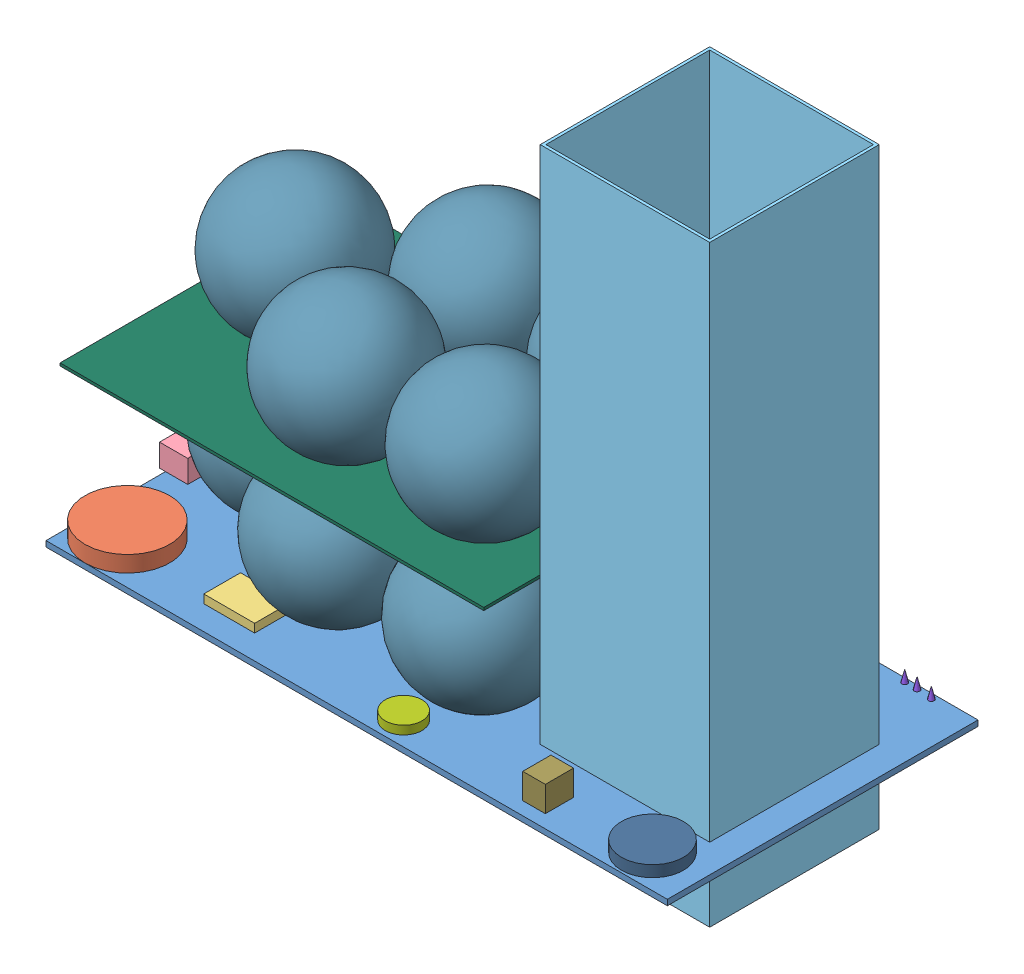
SolidWorks assembly layout_Assem1, configuration Default. Lengths in mm.
Overall size (2290.79 2100 2009.98).
28 component instances, 15 part files, 31 mates.
Components (placement in the parent):
- Rover_base-1: Rover_base [Default] at (-1064.6676 -0.8898 562.4151) size (2200 20 1100)
- Neutron_spectrometer-1: Neutron_spectrometer [Default] at (-926.7762 19.1102 412.2415) size (300 57 300)
- Neutron_spectrometer_electronics-1: Neutron_spectrometer_electronics [Default] at (-591.6675 19.1102 476.7062) size (180 30 130)
- gc-1: gc [Default] at (-1085.6976 19.1102 139.436) size (100 80 100)
- svr_box-1: svr_box [Default] at (435.3324 -241.6306 312.4151) size (600 2100 600)
- xrf-1: xrf [Default] at (-995.9409 19.1102 -179.1913) size (80 90 80)
- geotechnical_exp-1: geotechnical_exp [Default] at (118.8439 19.1102 479.7148) x (0.999975 0 -0.007135) z (0.007135 0 0.999975) size (130 30 130)
- penetrometer_3-1: penetrometer_3 [Default] at (989.1282 19.1102 -518.5473) x (-0.60186 0 0.798602) z (-0.798602 0 -0.60186) size (20 40 20)
- penetrometer_3-2: penetrometer_3 [Default] at (934.1975 19.1102 -522.9905) size (20 40 20)
- penetrometer_3-3: penetrometer_3 [Default] at (890.3988 19.1102 -523.0172) x (0.957231 0 -0.289323) z (0.289323 0 0.957231) size (20 40 20)
- power-1: power [Default] at (-567.0372 19.1102 -253.9622) size (180 90 96)
- geotechnical_exp_vane-1: geotechnical_exp_vane [Default] at (965.2252 19.1102 444.9326) size (220 40 220)
- Magnents-1: Magnents [Default] at (-1020.4169 -10.8898 98.2252) size (45 10 45)
- Becon-1: Becon [Default] at (656.9367 19.1102 515.9957) size (80 90 100)
- Belly Cam-1: Belly Cam [Default] at (-624.94 -100.8898 134.6139) size (150 100 150)
- power_tank-1: power_tank [Default] at (-887.862 555.3324 -63.369) x (-0.812429 0.027314 0.58242) z (0.582091 -0.01957 0.812888) size (1560.46 846.95 1367.46)
  - power_tank_10-1: power_tank_10 [Default] at (-67.1815 281.3265 414.5148) size (500 500 500)
  - power_tank_10-2: power_tank_10 [Default] at (-251.8267 476.4977 723.0274) x (0.786037 -0.315714 0.53148) z (0.083274 0.905991 0.415025) size (500 500 500)
  - power_tank_10-3: power_tank_10 [Default] at (-733.4982 325.3571 380.2859) x (0.665484 -0.133715 0.734337) z (-0.678573 0.301428 0.669836) size (500 500 500)
  - power_tank_10-4: power_tank_10 [Default] at (-1034.3616 424.6302 664.9742) x (0.724325 0.588989 -0.358392) z (-0.233278 0.698521 0.676499) size (500 500 500)
  - power_tank_10-5: power_tank_10 [Default] at (-695.3433 297.5492 1147.5051) x (0.994968 0.097333 0.023775) z (-0.042044 0.190197 0.980845) size (500 500 500)
- Tank_seperator_plate-1: Tank_seperator_plate [Default] at (435.3324 529.1102 512.4151) size (1500 10 1000)
- power_tank-3: power_tank [Default] at (-887.862 502.888 93.4377) x (-0.812429 -0.027314 -0.58242) z (0.582091 0.01957 -0.812888) size (1560.46 846.95 1367.46)
  - power_tank_10-1: power_tank_10 [Default] at (-67.1815 281.3265 414.5148) size (500 500 500)
  - power_tank_10-2: power_tank_10 [Default] at (-251.8267 476.4977 723.0274) x (0.786037 -0.315714 0.53148) z (0.083274 0.905991 0.415025) size (500 500 500)
  - power_tank_10-3: power_tank_10 [Default] at (-733.4982 325.3571 380.2859) x (0.665484 -0.133715 0.734337) z (-0.678573 0.301428 0.669836) size (500 500 500)
  - power_tank_10-4: power_tank_10 [Default] at (-1034.3616 424.6302 664.9742) x (0.724325 0.588989 -0.358392) z (-0.233278 0.698521 0.676499) size (500 500 500)
  - power_tank_10-5: power_tank_10 [Default] at (-695.3433 297.5492 1147.5051) x (0.994968 0.097333 0.023775) z (-0.042044 0.190197 0.980845) size (500 500 500)
Mates (geometry in assembly coordinates):
- Coincident2: coincident anti-aligned: plane of Rover_base-1 through (-1064.6676 19.1102 -537.5849) normal (0 1 0); plane of Neutron_spectrometer-1 through (-926.7762 19.1102 412.2415) normal (0 -1 0)
- Coincident6: coincident anti-aligned: plane of Rover_base-1 through (-1064.6676 19.1102 -537.5849) normal (0 1 0); plane of Neutron_spectrometer_electronics-1 through (-591.6675 19.1102 346.7062) normal (0 -1 0)
- Coincident7: coincident anti-aligned: plane of Rover_base-1 through (-1064.6676 19.1102 -537.5849) normal (0 1 0); plane of power-1 through (-567.0372 19.1102 -349.9622) normal (0 -1 0)
- Coincident8: coincident anti-aligned: plane of Rover_base-1 through (-1064.6676 19.1102 -537.5849) normal (0 1 0); plane of gc-1 through (-1085.6976 19.1102 39.436) normal (0 -1 0)
- Coincident9: coincident aligned: plane of Rover_base-1 through (-1064.6676 19.1102 -537.5849) normal (0 1 0); circle of geotechnical_exp-1 centre (118.8439 19.1102 479.7148) axis (0 1 0)
- Coincident10: coincident anti-aligned: plane of Rover_base-1 through (-1064.6676 19.1102 -537.5849) normal (0 1 0); plane of xrf-1 through (-995.9409 19.1102 -179.1913) normal (0 -1 0)
- Coincident11: coincident aligned: plane of Rover_base-1 through (-1064.6676 19.1102 -537.5849) normal (0 1 0); circle of penetrometer_3-3 centre (890.3988 19.1102 -523.0172) axis (0 1 0)
- Coincident12: coincident anti-aligned: plane of Rover_base-1 through (-1064.6676 19.1102 -537.5849) normal (0 1 0); plane of penetrometer_3-2 through (934.1975 19.1102 -522.9905) normal (0 -1 0)
- Coincident13: coincident aligned: plane of Rover_base-1 through (-1064.6676 19.1102 -537.5849) normal (0 1 0); circle of penetrometer_3-1 centre (989.1282 19.1102 -518.5473) axis (0 1 0)
- Coincident14: coincident anti-aligned: plane of Rover_base-1 through (-1064.6676 19.1102 -537.5849) normal (0 1 0); plane of geotechnical_exp_vane-1 through (965.2252 19.1102 444.9326) normal (0 -1 0)
- Coincident15: coincident anti-aligned: plane of Rover_base-1 through (-1064.6676 -0.8898 -537.5849) normal (0 -1 0); plane of Magnents-1 through (-1020.4169 -0.8898 98.2252) normal (0 1 0)
- Coincident16: coincident anti-aligned: plane of Rover_base-1 through (-1064.6676 19.1102 -537.5849) normal (0 1 0); plane of Becon-1 through (656.9367 19.1102 515.9957) normal (0 -1 0)
- Tangent1: tangent anti-aligned: plane of Rover_base-1 through (-1064.6676 19.1102 -537.5849) normal (0 1 0); sphere of power_tank-1/power_tank_10-1
- Coincident18: coincident: line of Rover_base-1; plane of svr_box-1 through (435.3324 1858.3694 312.4151) normal (-1 0 0)
- Coincident20: coincident: line of Rover_base-1; plane of svr_box-1 through (435.3324 1858.3694 -287.5849) normal (0 0 -1)
- Perpendicular2: perpendicular: line of Rover_base-1; line of svr_box-1
- Perpendicular3: perpendicular: line of Rover_base-1; line of svr_box-1
- Perpendicular4: perpendicular: line of Rover_base-1; line of svr_box-1
- Tangent12: tangent anti-aligned: plane of Rover_base-1 through (-1064.6676 19.1102 -537.5849) normal (0 1 0); sphere of power_tank-1/power_tank_10-4
- Tangent13: tangent anti-aligned: plane of Rover_base-1 through (-1064.6676 19.1102 -537.5849) normal (0 1 0); sphere of power_tank-1/power_tank_10-5
- Tangent15: tangent anti-aligned: plane of svr_box-1 through (435.3324 1858.3694 312.4151) normal (-1 0 0); sphere of power_tank-1/power_tank_10-4
- Tangent16: tangent anti-aligned: plane of svr_box-1 through (435.3324 1858.3694 312.4151) normal (-1 0 0); sphere of power_tank-1/power_tank_10-5
- Coincident25: coincident anti-aligned: plane of svr_box-1 through (435.3324 1858.3694 312.4151) normal (-1 0 0); plane of Tank_seperator_plate-1 through (435.3324 539.1102 512.4151) normal (1 0 0)
- Parallel1: parallel anti-aligned: plane of Rover_base-1 through (-1064.6676 19.1102 -537.5849) normal (0 1 0); plane of Tank_seperator_plate-1 through (435.3324 529.1102 512.4151) normal (0 -1 0)
- Distance3: distance = 200 mm: line of svr_box-1; point of Tank_seperator_plate-1
- Distance4: distance = 510 mm: plane of Rover_base-1 through (-1064.6676 19.1102 -537.5849) normal (0 1 0); line of Tank_seperator_plate-1
- Tangent29: tangent anti-aligned: plane of svr_box-1 through (435.3324 1858.3694 312.4151) normal (-1 0 0); sphere of power_tank-3/power_tank_10-5
- Tangent30: tangent anti-aligned: plane of svr_box-1 through (435.3324 1858.3694 312.4151) normal (-1 0 0); sphere of power_tank-3/power_tank_10-4
- Tangent32: tangent anti-aligned: plane of Tank_seperator_plate-1 through (435.3324 539.1102 512.4151) normal (0 1 0); sphere of power_tank-3/power_tank_10-1
- Tangent33: tangent anti-aligned: plane of Tank_seperator_plate-1 through (435.3324 539.1102 512.4151) normal (0 1 0); sphere of power_tank-3/power_tank_10-4
- Tangent34: tangent anti-aligned: plane of Tank_seperator_plate-1 through (435.3324 539.1102 512.4151) normal (0 1 0); sphere of power_tank-3/power_tank_10-5
